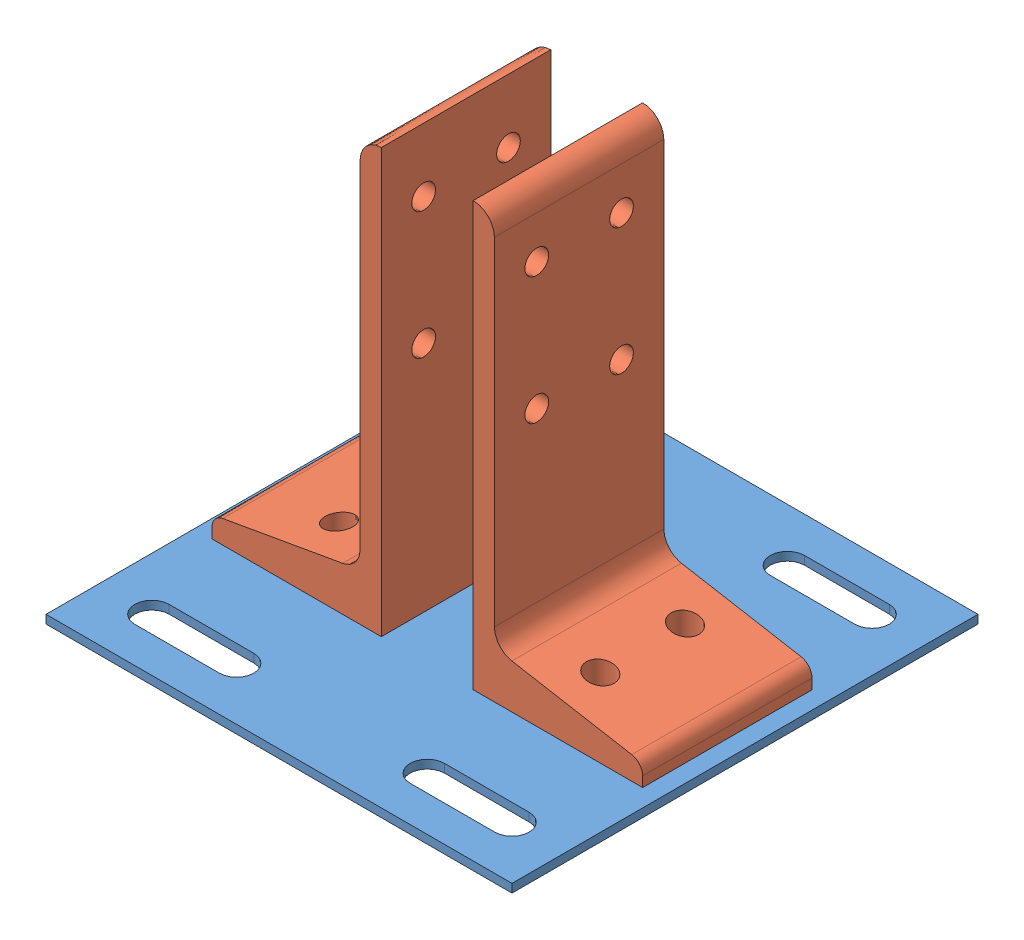
SolidWorks assembly 8020-2385, configuration Default. Lengths in mm.
Overall size (139.7 129.54 139.7).
3 component instances, 2 part files, 6 mates.
Components (placement in the parent):
- 8020-2385_238508-1: 8020-2385_238508 [Default] at (-2.8656 4.3503 -15.9353) size (139.7 2.54 139.7)
- 8020-2385_238509-1: 8020-2385_238509 [Default] at (29.7024 -6.8087 -25.6289) size (50.8 127 50.8)
- 8020-2385_238509-2: 8020-2385_238509 [Default] at (-43.307 -6.8087 25.1711) x (-1 0 0) z (0 0 -1) size (50.8 127 50.8)
Mates (geometry in assembly coordinates):
- Coincident1: coincident anti-aligned: plane of 8020-2385_238508-1 through (-2.8656 6.8903 -15.9353) normal (0 1 0); plane of 8020-2385_238509-2 through (-43.307 6.8903 -25.6289) normal (0 -1 0)
- Coincident2: coincident anti-aligned: plane of 8020-2385_238508-1 through (-2.8656 6.8903 -15.9353) normal (0 1 0); plane of 8020-2385_238509-1 through (29.7024 6.8903 25.1711) normal (0 -1 0)
- Concentric1: concentric aligned: circle of 8020-2385_238508-1; cylinder of 8020-2385_238509-2 through (-45.9691 133.8903 -12.9289) axis (0 -1 0) radius 4.1656
- Concentric2: concentric aligned: circle of 8020-2385_238508-1; cylinder of 8020-2385_238509-2 through (-45.9691 133.8903 12.4711) axis (0 -1 0) radius 4.1656
- Concentric3: concentric aligned: circle of 8020-2385_238508-1; circle of 8020-2385_238509-1
- Concentric4: concentric aligned: circle of 8020-2385_238508-1; cylinder of 8020-2385_238509-1 through (32.3645 133.8903 -12.9289) axis (0 -1 0) radius 4.1656
